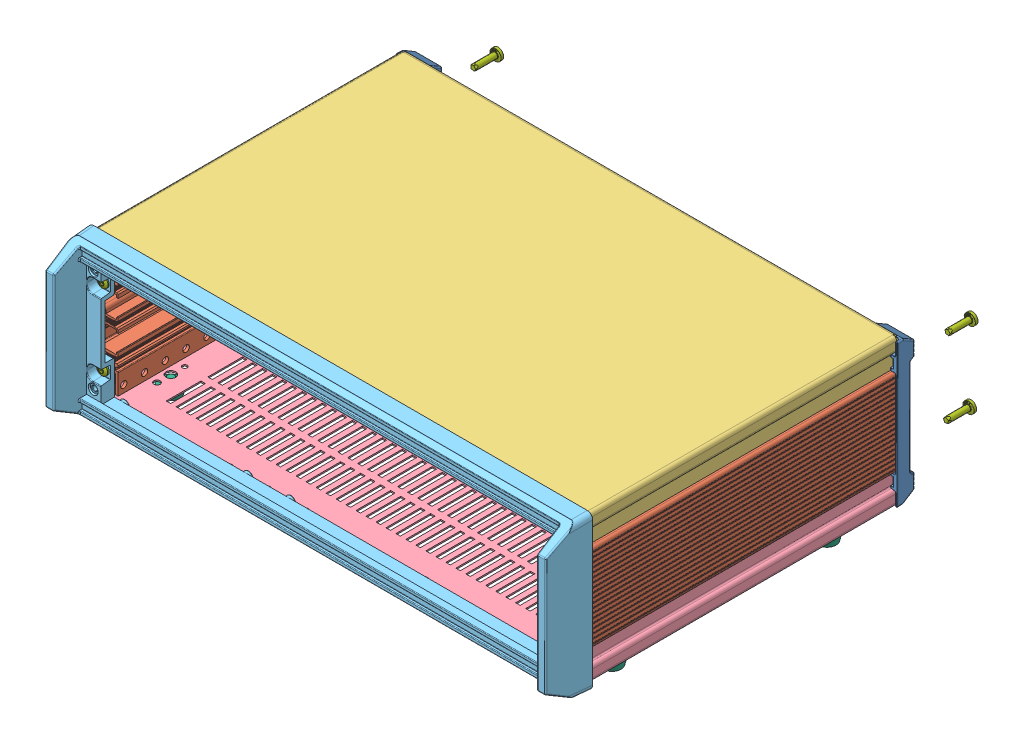
SolidWorks assembly Сборка1, configuration По умолчанию. Lengths in mm.
Overall size (363.7 119.35 320.9).
26 component instances, 11 part files, 49 mates.
Components (placement in the parent):
- RUECKFUSS-2HE-vereinfacht-1: RUECKFUSS-2HE-vereinfacht [По умолчанию] at (-233.9301 101.2807 -302.9158) x (-0.000005 0 1) z (-1 0 -0.000005) size (20.51 103.44 20.8)
- RUECKFUSS-2HE-vereinfacht-2: RUECKFUSS-2HE-vereinfacht [По умолчанию] at (127.7698 56.7192 -302.9174) x (0.000005 0 1) z (1 0 -0.000005) size (20.51 103.44 20.8)
- SEITENWAND-2HE-266T-1: SEITENWAND-2HE-266T [По умолчанию] at (111.3199 61.7249 -241.287) x (0 1 0) z (0 0 -1) size (88.1 16.5 221.6)
- SEITENWAND-2HE-266T-2: SEITENWAND-2HE-266T [По умолчанию] at (-217.4799 96.2749 -241.287) x (0 -1 0) z (0 0 -1) size (88.1 16.5 221.6)
- MANTEL-OB-----266T------63TE-1: MANTEL-OB-----266T------63TE [По умолчанию] at (-158.6168 132.7509 -217.2965) x (-1 0 0) z (0 -1 0) size (358.09 224.85 32)
- MANTEL-UN-----266T------63TE-1: MANTEL-UN-----266T------63TE [По умолчанию] at (52.3767 26.7512 -217.2965) x (1 0 0) z (0 1 0) size (358.08 224.91 32)
- RAHMEN-2HE-63TE-1: RAHMEN-2HE-63TE [По умолчанию] at (-53.3301 78.9999 -56.5797) size (363.7 111.05 35.05)
- 60224009-1: 60224009 [По умолчанию] at (-161.3888 93.3488 -98.087) x (1 0 0) z (0 0 1) size (16 11.2 16)
- 60224009-2: 60224009 [По умолчанию] at (-161.3888 93.3488 -243.087) x (1 0 0) z (0 0 1) size (16 11.2 16)
- 60224009-3: 60224009 [По умолчанию] at (166.6912 93.3488 -88.087) x (1 0 0) z (0 0 1) size (16 11.2 16)
- 60224009-4: 60224009 [По умолчанию] at (166.6912 93.3487 -243.087) x (1 0 0) z (0 0 1) size (16 11.2 16)
- FLKOSHR-T-M-4-X16--1: FLKOSHR-T-M-4-X16- [По умолчанию] at (-221.18 106.2499 -56.5574) size (8.2 9.29 19.12)
- FLKOSHR-T-M-4-X16--2: FLKOSHR-T-M-4-X16- [По умолчанию] at (-221.18 51.7499 -56.2556) size (8.2 9.29 19.12)
- FLKOSHR-T-M-4-X16--3: FLKOSHR-T-M-4-X16- [По умолчанию] at (115.0199 106.2499 -57.7385) size (8.2 9.29 19.12)
- FLKOSHR-T-M-4-X16--4: FLKOSHR-T-M-4-X16- [По умолчанию] at (115.0199 51.7499 -57.6769) size (8.2 9.29 19.12)
- FLKOSHR-T-M-4-X16--5: FLKOSHR-T-M-4-X16- [По умолчанию] at (115.0199 51.7499 -339.0651) x (0.124102 -0.992269 0) z (0 0 -1) size (8.2 9.29 19.12)
- FLKOSHR-T-M-4-X16--6: FLKOSHR-T-M-4-X16- [По умолчанию] at (115.0199 106.2499 -340.0788) x (-0.133956 -0.990987 0) z (0 0 -1) size (8.2 9.29 19.12)
- FLKOSHR-T-M-4-X16--7: FLKOSHR-T-M-4-X16- [По умолчанию] at (-221.18 51.7499 -332.8539) x (-0.867641 -0.49719 0) z (0 0 -1) size (8.2 9.29 19.12)
- FLKOSHR-T-M-4-X16--8: FLKOSHR-T-M-4-X16- [По умолчанию] at (-221.18 106.2499 -334.2196) x (-0.33567 0.94198 0) z (0 0 -1) size (8.2 9.29 19.12)
- 34560763_3D-1: 34560763_3D [По умолчанию] at (-52.9494 113.5499 -249.787) x (1 0 0) z (0 0 -1) size (325.12 9 30.5)
- 34560763_3D-2: 34560763_3D [По умолчанию] at (-52.9494 36.0499 -249.787) x (1 0 0) z (0 0 -1) size (325.12 9 30.5)
- 34561363_3D-1: 34561363_3D [По умолчанию] at (-52.6994 122.6245 -277.687) size (324.62 5 2)
- 34561363_3D-2: 34561363_3D [По умолчанию] at (-52.6994 45.1245 -277.687) size (324.62 5 2)
- 30849015-2: 30849015 [По умолчанию] at (-103.8512 85.0983 -272.5208) size (319.7 83.95 2.5)
- 30845232_3D-1: 30845232_3D [По умолчанию] at (-52.8494 122.6245 -284.987) size (324.92 5 1)
- 30845232_3D-2: 30845232_3D [По умолчанию] at (-52.8494 45.1245 -284.987) size (324.92 5 1)
Mates (geometry in assembly coordinates):
- Совпадение1: coincident aligned: plane of 60224009-1 through (-212.43 15.1815 -102.817) normal (0 -1 0); plane of 60224009-2 through (-212.43 15.1815 -247.817) normal (0 -1 0)
- Совпадение2: coincident aligned: plane of 60224009-2 through (-212.43 15.1815 -247.817) normal (0 -1 0); plane of 60224009-4 through (115.65 15.1815 -247.817) normal (0 -1 0)
- Совпадение3: coincident aligned: plane of 60224009-3 through (115.65 15.1815 -92.817) normal (0 -1 0); plane of 60224009-4 through (115.65 15.1815 -247.817) normal (0 -1 0)
- Концентричный1: concentric aligned: cylinder of MANTEL-UN-----266T------63TE-1 through (-217.16 26.7513 -243.087) axis (0 1 0) radius 3.5; circle of 60224009-2
- Концентричный2: concentric aligned: cylinder of MANTEL-UN-----266T------63TE-1 through (110.92 26.7512 -243.087) axis (0 1 0) radius 3.5; circle of 60224009-4
- Концентричный3: concentric aligned: cylinder of MANTEL-UN-----266T------63TE-1 through (110.92 26.7512 -88.087) axis (0 1 0) radius 2.25; circle of 60224009-3
- Концентричный4: concentric aligned: cylinder of MANTEL-UN-----266T------63TE-1 through (-217.16 26.7513 -98.087) axis (0 1 0) radius 3.5; circle of 60224009-1
- Совпадение4: coincident anti-aligned: plane of SEITENWAND-2HE-266T-1 through (122.42 49.9093 -58.287) normal (-1 0 0); plane of MANTEL-UN-----266T------63TE-1 through (122.42 38.4212 -279.217) normal (1 0 0)
- Совпадение5: coincident anti-aligned: plane of SEITENWAND-2HE-266T-1 through (108.7074 124.2512 -279.887) normal (0 0 -1); plane of MANTEL-UN-----266T------63TE-1 through (-229.56 58.7513 -279.887) normal (0 0 1)
- Совпадение6: coincident aligned: plane of SEITENWAND-2HE-266T-1 through (109.2199 123.05 -58.287) normal (0 1 0); plane of SEITENWAND-2HE-266T-2 through (-215.3799 123.05 -58.287) normal (0 1 0)
- Совпадение7: coincident aligned: plane of SEITENWAND-2HE-266T-1 through (108.7074 124.2512 -279.887) normal (0 0 -1); plane of SEITENWAND-2HE-266T-2 through (-214.8674 33.7486 -279.887) normal (0 0 -1)
- Расстояние1: distance = 351 mm: plane of SEITENWAND-2HE-266T-1 through (122.42 49.9093 -58.287) normal (-1 0 0); point of SEITENWAND-2HE-266T-2
- Концентричный5: concentric anti-aligned: circle of SEITENWAND-2HE-266T-1; circle of FLKOSHR-T-M-4-X16--6
- Концентричный6: concentric aligned: circle of SEITENWAND-2HE-266T-1; circle of FLKOSHR-T-M-4-X16--5
- Концентричный7: concentric aligned: circle of SEITENWAND-2HE-266T-2; circle of FLKOSHR-T-M-4-X16--8
- Концентричный8: concentric anti-aligned: circle of SEITENWAND-2HE-266T-2; circle of FLKOSHR-T-M-4-X16--7
- Концентричный9: concentric aligned: cone of RUECKFUSS-2HE-vereinfacht-1 through (-221.18 106.2499 -287.0277) axis (0 0 1); circle of FLKOSHR-T-M-4-X16--8
- Перпендикулярность1: perpendicular: plane of RUECKFUSS-2HE-vereinfacht-1 through (-233.9299 123.775 -289.0275) normal (0 -0.999391 -0.034899); plane of SEITENWAND-2HE-266T-2 through (-229.88 86.1999 -58.287) normal (1 0 0)
- Концентричный10: concentric aligned: cone of RUECKFUSS-2HE-vereinfacht-2 through (115.0199 106.2499 -287.0293) axis (0 0 1); circle of FLKOSHR-T-M-4-X16--6
- Перпендикулярность2: perpendicular: plane of RUECKFUSS-2HE-vereinfacht-2 through (127.7699 123.775 -289.0292) normal (0 -0.999391 -0.034899); plane of SEITENWAND-2HE-266T-1 through (123.7199 86.1999 -58.287) normal (-1 0 0)
- Концентричный11: concentric aligned: circle of SEITENWAND-2HE-266T-2; circle of FLKOSHR-T-M-4-X16--1
- Концентричный12: concentric anti-aligned: circle of SEITENWAND-2HE-266T-2; circle of FLKOSHR-T-M-4-X16--2
- Концентричный13: concentric anti-aligned: circle of SEITENWAND-2HE-266T-1; circle of FLKOSHR-T-M-4-X16--3
- Концентричный14: concentric aligned: circle of SEITENWAND-2HE-266T-1; circle of FLKOSHR-T-M-4-X16--4
- Концентричный15: concentric anti-aligned: cone of RAHMEN-2HE-63TE-1 through (115.0199 51.7499 -53.5797) axis (0 0 1); circle of FLKOSHR-T-M-4-X16--4
- Перпендикулярность3: perpendicular: plane of SEITENWAND-2HE-266T-1 through (123.7199 86.1999 -58.287) normal (-1 0 0); plane of RAHMEN-2HE-63TE-1 through (-216.6419 123.2296 -46.4797) normal (0 -1 0)
- Совпадение9: coincident anti-aligned: plane of SEITENWAND-2HE-266T-1 through (122.42 108.0905 -58.287) normal (-1 0 0); plane of MANTEL-OB-----266T------63TE-1 through (122.42 121.0809 -56.057) normal (1 0 0)
- Расстояние2: distance = 0 mm: plane of SEITENWAND-2HE-266T-1 through (108.7074 124.2512 -279.887) normal (0 0 -1); point of MANTEL-OB-----266T------63TE-1
- Перпендикулярность4: perpendicular: plane of MANTEL-OB-----266T------63TE-1 through (-229.56 131.7509 -278.287) normal (0 -1 0); plane of SEITENWAND-2HE-266T-1 through (108.7074 124.2512 -279.887) normal (0 0 -1)
- Концентричный16: concentric aligned: cylinder of SEITENWAND-2HE-266T-1 through (111.2199 117.7499 -242.287) axis (-1 0 0) radius 2.3; circle of 34560763_3D-1
- Концентричный17: concentric aligned: cylinder of SEITENWAND-2HE-266T-1 through (111.2199 117.7499 -257.287) axis (-1 0 0) radius 2.3; circle of 34560763_3D-1
- Концентричный18: concentric aligned: cylinder of SEITENWAND-2HE-266T-1 through (111.2199 40.2499 -242.287) axis (-1 0 0) radius 2.3; circle of 34560763_3D-2
- Концентричный19: concentric aligned: circle of SEITENWAND-2HE-266T-1; circle of 34560763_3D-2
- Совпадение12: coincident anti-aligned: plane of 34560763_3D-1 through (109.6106 120.6495 -262.637) normal (0 0 -1); plane of 34561363_3D-1 through (110.5876 114.9245 -262.637) normal (0 0 1)
- Совпадение13: coincident anti-aligned: plane of 34560763_3D-1 through (109.6106 120.6495 -264.837) normal (0 -1 0); plane of 34561363_3D-1 through (-215.8594 120.6495 -262.037) normal (0 1 0)
- Совпадение14: coincident aligned: plane of 34560763_3D-1 through (109.6106 122.1749 -270.7995) normal (1 0 0); plane of 34561363_3D-1 through (109.6106 120.1495 -265.137) normal (1 0 0)
- Совпадение15: coincident anti-aligned: plane of 34560763_3D-2 through (109.6106 43.1495 -262.637) normal (0 0 -1); plane of 34561363_3D-2 through (110.5876 37.4245 -262.637) normal (0 0 1)
- Совпадение16: coincident anti-aligned: plane of 34560763_3D-2 through (109.6106 43.1495 -264.837) normal (0 -1 0); plane of 34561363_3D-2 through (-215.8594 43.1495 -262.037) normal (0 1 0)
- Совпадение17: coincident aligned: plane of 34560763_3D-2 through (109.6106 44.6749 -270.7995) normal (1 0 0); plane of 34561363_3D-2 through (109.6106 42.6495 -265.137) normal (1 0 0)
- Совпадение18: coincident aligned: plane of 34560763_3D-1 through (109.6106 122.1749 -270.7995) normal (1 0 0); plane of 34560763_3D-2 through (109.6106 44.6749 -270.7995) normal (1 0 0)
- Ширина1: width aligned: plane of 34560763_3D-1 through (109.6106 119.7995 -266.837) normal (0 -1 0); plane of 34560763_3D-1 through (109.6106 116.2495 -264.837) normal (0 1 0); plane of 30849015-2 through (104.606 119.6745 -272.5208) normal (0 -1 0); plane of 30849015-2 through (99.7152 116.3745 -272.5208) normal (0 1 0)
- Совпадение19: coincident aligned: plane of 34560763_3D-1 through (109.6106 122.1749 -270.7995) normal (1 0 0); plane of 30849015-2 through (109.6106 121.0245 -272.5208) normal (1 0 0)
- Расстояние3: distance = 0 mm: plane of RUECKFUSS-2HE-vereinfacht-2 through (127.9699 157.5976 -287.0292) normal (-0.000005 0 -1); point of RUECKFUSS-2HE-vereinfacht-1
- Совпадение21: coincident anti-aligned: plane of 34560763_3D-1 through (109.6106 120.6495 -266.837) normal (0 0 -1); plane of 30845232_3D-1 through (110.4376 114.9245 -266.837) normal (0 0 1)
- Совпадение22: coincident anti-aligned: plane of 34560763_3D-1 through (109.6106 120.6495 -268.037) normal (0 -1 0); plane of 30845232_3D-1 through (-216.0094 120.6495 -266.237) normal (0 1 0)
- Совпадение23: coincident aligned: plane of 34560763_3D-1 through (109.6106 122.1749 -270.7995) normal (1 0 0); plane of 30845232_3D-1 through (109.6106 120.1495 -268.837) normal (1 0 0)
- Совпадение24: coincident anti-aligned: plane of 34560763_3D-2 through (109.6106 43.1495 -266.837) normal (0 0 -1); plane of 30845232_3D-2 through (110.4376 37.4245 -266.837) normal (0 0 1)
- Совпадение25: coincident anti-aligned: plane of 34560763_3D-2 through (109.6106 43.1495 -268.037) normal (0 -1 0); plane of 30845232_3D-2 through (-216.0094 43.1495 -266.237) normal (0 1 0)
- Совпадение26: coincident aligned: plane of 34560763_3D-2 through (109.6106 44.6749 -270.7995) normal (1 0 0); plane of 30845232_3D-2 through (109.6106 42.6495 -268.837) normal (1 0 0)
